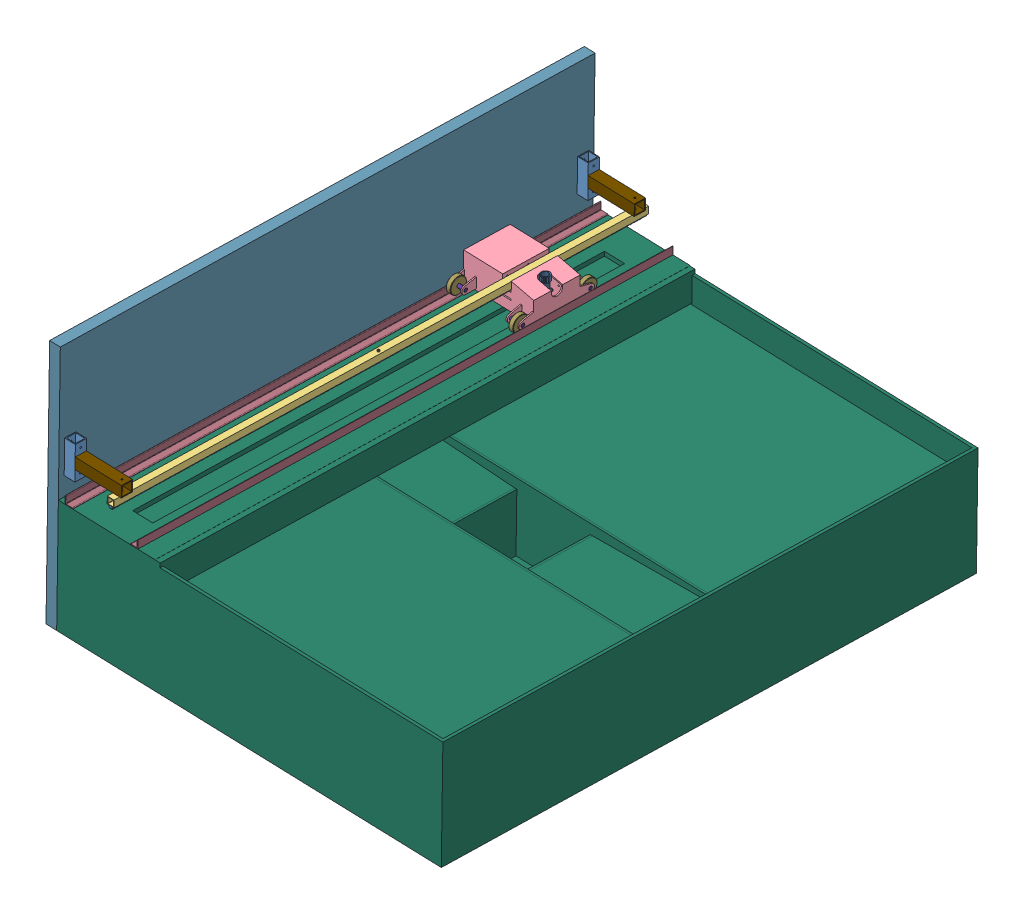
SolidWorks assembly Assembly4, configuration Default. Lengths in mm.
Overall size (969.13 588.82 1240.57).
33 component instances, 21 part files, 57 mates.
Components (placement in the parent):
- 6295K232_MTL GEAR RACK--14-.5 DEG PRESSURE ANGLE-1: 6295K232_MTL GEAR RACK--14-.5 DEG PRESSURE ANGLE [6295K232] at (310.8168 -1313.8551 1072.8368) x (-0.021222 0.003141 0.99977) z (0.999705 -0.011724 0.021258) size (1219.2 6.35 6.35)
- 91251A113_BLACK-OXIDE ALLOY STEEL SOCKET HEAD CAP SCREW-1: 91251A113_BLACK-OXIDE ALLOY STEEL SOCKET HEAD CAP SCREW [91251A113] at (324.3007 -1313.7028 488.7881) x (-0.325939 0.001109 -0.94539) z (-0.011788 -0.999926 0.002892) size (4.65 4.65 22.32)
- RackBacking1-1: RackBacking1 [Default] at (331.9137 -1296.8145 463.4908) x (-0.021222 0.003141 0.99977) z (0.999705 -0.011724 0.021258) size (1219.2 15.88 15.88)
- 91251A113_BLACK-OXIDE ALLOY STEEL SOCKET HEAD CAP SCREW-2: 91251A113_BLACK-OXIDE ALLOY STEEL SOCKET HEAD CAP SCREW [91251A113] at (311.8789 -1313.8675 1072.8599) x (0.97426 -0.010834 0.225168) z (-0.011788 -0.999926 0.002892) size (4.65 4.65 22.32)
- 91251A113_BLACK-OXIDE ALLOY STEEL SOCKET HEAD CAP SCREW-3: 91251A113_BLACK-OXIDE ALLOY STEEL SOCKET HEAD CAP SCREW [91251A113] at (298.4422 -1310.02 1656.8966) x (0.959532 -0.012125 -0.281339) z (-0.011788 -0.999926 0.002892) size (4.65 4.65 22.32)
- Machine Design Assembly 1-2: Machine Design Assembly 1 [Default] at (1783.6413 -1774.7263 1512.3615) x (-0.115648 -0.280931 0.952735) z (-0.993045 0.011368 -0.117189) size (198.29 116.63 182.75)
  - quarterInchCoupler-1: quarterInchCoupler [6412K11] at (-37.8277 473.4587 1102.0251) x (0.998807 -0.00133 -0.04881) z (0.04881 0.054423 0.997324) size (12.7 13.7 19.05) (hidden)
  - Main_Housing-2: Main_Housing [Default] at (-642.996 231.7633 1650.4471) x (0.092068 0.027377 0.995376) z (-0.954087 -0.28371 0.096052) size (167 66 172)
  - Nema23 Stepper Motor-4: Nema23 Stepper Motor [Default] at (-681.5334 251.0803 1647.4525) x (0.954156 0.283479 -0.096052) z (-0.284798 0.958588 -0.000023) size (56.4 82.6 56.4)
  - Stepper Motor Nema 23 Shaft-3: Stepper Motor Nema 23 Shaft [Default] at (-690.7402 248.3426 1547.9149) x (0.995752 -0.001263 -0.092068) z (0.001263 -0.999624 0.027377) size (6.35 100 6.35)
  - Raspberry Pi 3-4: Raspberry Pi 3 [Default] at (-718.0254 233.7658 1618.7368) x (0.092068 0.027377 0.995376) z (-0.954087 -0.28371 0.096052) size (87.38 57.31 18.74)
  - Motor Shield-3: Motor Shield [Default] at (-733.2486 231.7541 1604.1842) x (0.092068 0.027377 0.995376) z (0.285028 -0.958519 0) size (64.5 8 55.5)
  - Stepper Motor Nema 17-3: Stepper Motor Nema 17 [25mm] at (-737.1607 226.7143 1522.6641) x (-0.28371 0.958809 0.013946) z (0.096052 0.013946 0.995279) size (42.3 49 42.3)
  - SolenoidValve-2: SolenoidValve [Default] at (-720.821 271.3165 1521.0428) x (0.954087 0.28371 -0.096052) z (0.103924 -0.012791 0.994503) size (61 71.38 34)
  - 6867K557_MTL GEAR--14-.5 DEG PRESSURE ANGLE-4: 6867K557_MTL GEAR--14-.5 DEG PRESSURE ANGLE [6867K557] at (-690.7402 248.3426 1547.9149) x (-0.995752 0.001263 0.092068) z (-0.092068 -0.027377 -0.995376) size (17.7 17.8 14.31)
  - Main_Housing_Lid_Final-1: Main_Housing_Lid_Final [Default] at (-642.1409 228.8877 1650.4471) x (-0.092068 -0.027377 -0.995376) z (0.285028 -0.958519 0) size (167 106 3) (hidden)
- wheel-2: wheel [Default] at (362.4104 -1345.0753 801.4369) x (-0.000289 -0.881336 -0.472491) z (-0.024275 -0.472345 0.881079) size (37.19 11 37.19)
- wheel-3: wheel [Default] at (213.4543 -1343.3284 798.2695) x (0.018928 -0.171894 -0.984934) z (-0.015201 -0.985046 0.171621) size (37.19 11 37.19)
- wheel-4: wheel [Default] at (366.6783 -1345.5708 647.4936) x (-0.00534 -0.960411 -0.278535) z (-0.023682 -0.27834 0.960191) size (37.19 11 37.19)
- wheel-5: wheel [Default] at (216.7225 -1343.8122 644.3049) x (0.002635 -0.81808 -0.575099) z (-0.024133 -0.574985 0.817808) size (37.19 11 37.19)
- L_Rails-1: L_Rails [Default] at (363.0838 -1344.6368 1683.7834) x (-0.011788 -0.999926 0.002892) z (0.999705 -0.011724 0.021258) size (18.01 1220.02 18.43)
- L_Rails-2: L_Rails [Default] at (216.0262 -1346.441 460.3866) x (-0.011788 -0.999926 0.002892) z (-0.999705 0.011724 -0.021258) size (18.01 1220.02 18.43)
- box-2: box [Default] at (171.2972 -1627.9323 461.1217) x (-0.021222 0.003141 0.99977) z (-0.999705 0.011724 -0.021258) size (1219.2 574 25.4)
- Demo_Enclosure-1: Demo_Enclosure [Default] at (641.1262 -1631.6802 1080.447) x (-0.021222 0.003141 0.99977) z (-0.999705 0.011724 -0.021258) size (1220 264 915)
- 12V DC Water Oil Pump-1: 12V DC Water Oil Pump [Default] at (447.0384 -1543.9402 903.9389) x (0.000017 0.002892 0.999996) z (-0.999931 0.011788 -0.000017) size (45.68 66.45 82.5)
- wheelShaft-6: wheelShaft [Default] at (210.5551 -1343.2944 798.2079) x (-0.009506 -0.994781 -0.101588) z (-0.022338 -0.101356 0.994599) size (8.25 30.9 8.25)
- wheelShaft-7: wheelShaft [Default] at (213.8234 -1343.7782 644.2433) x (-0.009506 -0.994781 -0.101588) z (-0.022338 -0.101356 0.994599) size (8.25 30.9 8.25)
- wheelShaft-8: wheelShaft [Default] at (346.515 -1344.8889 801.0989) x (-0.009506 -0.994781 -0.101588) z (-0.022338 -0.101356 0.994599) size (8.25 30.9 8.25)
- wheelShaft-9: wheelShaft [Default] at (349.7833 -1345.3727 647.1344) x (-0.009506 -0.994781 -0.101588) z (-0.022338 -0.101356 0.994599) size (8.25 30.9 8.25)
- straightBracket-1: straightBracket [Default] at (226.2611 -1295.4652 499.3526) x (0.021222 -0.003141 -0.99977) z (0.999705 -0.011724 0.021258) size (25.4 25.4 110)
- straightBracket2-1: straightBracket2 [Default] at (201.4674 -1244.3712 498.6657) x (0.021222 -0.003141 -0.99977) z (-0.011788 -0.999926 0.002892) size (25.4 25.4 76.2)
- straightBracket-2: straightBracket [Default] at (200.4025 -1291.7824 1667.4611) x (0.021222 -0.003141 -0.99977) z (0.999705 -0.011724 0.021258) size (25.4 25.4 110)
- straightBracket2-2: straightBracket2 [Default] at (201.5404 -1241.066 1641.92) x (-0.021222 0.003141 0.99977) z (-0.011788 -0.999926 0.002892) size (25.4 25.4 76.2)
Mates (geometry in assembly coordinates):
- Parallel1: parallel anti-aligned: cylinder of 6295K232_MTL GEAR RACK--14-.5 DEG PRESSURE ANGLE-1 through (323.2224 -1315.0553 488.7695) axis (0.011788 0.999926 -0.002892) radius 1.9647; cylinder of RackBacking1-1 through (324.5017 -1296.6541 488.7388) axis (-0.011788 -0.999926 0.002892) radius 2
- Coincident2: coincident anti-aligned: plane of 6295K232_MTL GEAR RACK--14-.5 DEG PRESSURE ANGLE-1 through (326.9655 -1312.6325 463.4355) normal (0.011788 0.999926 -0.002892); plane of RackBacking1-1 through (305.8521 -1308.8584 1682.4561) normal (-0.011788 -0.999926 0.002892)
- Concentric4: concentric aligned: cylinder of RackBacking1-1 through (312.1035 -1294.8189 1072.8048) axis (-0.011788 -0.999926 0.002892) radius 2; cylinder of 91251A113_BLACK-OXIDE ALLOY STEEL SOCKET HEAD CAP SCREW-2 through (312.137 -1291.9743 1072.7966) axis (-0.011788 -0.999926 0.002892) radius 2.3241
- Concentric6: concentric aligned: cylinder of 91251A113_BLACK-OXIDE ALLOY STEEL SOCKET HEAD CAP SCREW-1 through (324.5588 -1291.8096 488.7248) axis (-0.011788 -0.999926 0.002892) radius 2.3241; cylinder of RackBacking1-1 through (324.5017 -1296.6541 488.7388) axis (-0.011788 -0.999926 0.002892) radius 2
- Coincident4: coincident anti-aligned: plane of RackBacking1-1 through (306.0393 -1292.9845 1682.4102) normal (0.011788 0.999926 -0.002892); plane of 91251A113_BLACK-OXIDE ALLOY STEEL SOCKET HEAD CAP SCREW-2 through (312.1035 -1294.8189 1072.8048) normal (-0.011788 -0.999926 0.002892)
- Coincident14: coincident aligned: plane of 6295K232_MTL GEAR RACK--14-.5 DEG PRESSURE ANGLE-1 through (301.0162 -1315.1521 1682.3732) normal (0.999705 -0.011724 0.021258); plane of Machine Design Assembly 1-2/6867K557_MTL GEAR--14-.5 DEG PRESSURE ANGLE-4 through (320.8897 -1324.7549 742.4784) normal (0.999705 -0.011724 0.021258)
- Distance1: distance = 13 mm: point of Machine Design Assembly 1-2/6867K557_MTL GEAR--14-.5 DEG PRESSURE ANGLE-4; line of 6295K232_MTL GEAR RACK--14-.5 DEG PRESSURE ANGLE-1 through (326.9655 -1312.6325 463.4355) axis (-0.021222 0.003141 0.99977)
- Parallel6: parallel aligned: plane of RackBacking1-1 through (306.0393 -1292.9845 1682.4102) normal (0.011788 0.999926 -0.002892); plane of Machine Design Assembly 1-2/Main_Housing-2 through (213.7811 -1290.1962 671.0803) normal (0.011788 0.999926 -0.002892)
- Coincident17: coincident aligned: circle of Machine Design Assembly 1-2/Main_Housing-2; cylinder of wheel-2 through (362.4104 -1345.0753 801.4369) axis (0.999705 -0.011724 0.021258) radius 4.125
- Distance2: distance = 24 mm aligned: plane of wheel-2 through (373.4071 -1345.2043 801.6708) normal (0.999705 -0.011724 0.021258); plane of Machine Design Assembly 1-2/Main_Housing-2 through (349.4142 -1344.9229 801.1606) normal (0.999705 -0.011724 0.021258)
- Coincident24: coincident aligned: circle of Machine Design Assembly 1-2/Main_Housing-2; cylinder of wheel-3 through (213.4543 -1343.3284 798.2695) axis (0.999705 -0.011724 0.021258) radius 4.125
- Coincident25: coincident aligned: circle of Machine Design Assembly 1-2/Main_Housing-2; cylinder of wheel-4 through (366.6783 -1345.5708 647.4936) axis (0.999705 -0.011724 0.021258) radius 4.125
- Coincident26: coincident aligned: circle of Machine Design Assembly 1-2/Main_Housing-2; cylinder of wheel-5 through (216.7225 -1343.8122 644.3049) axis (0.999705 -0.011724 0.021258) radius 4.125
- Distance4: distance = 14 mm anti-aligned: plane of wheel-5 through (227.7193 -1343.9412 644.5388) normal (0.999705 -0.011724 0.021258); plane of Machine Design Assembly 1-2/Main_Housing-2 through (241.7152 -1344.1053 644.8364) normal (-0.999705 0.011724 -0.021258)
- Distance5: distance = 14 mm anti-aligned: plane of wheel-4 through (366.6783 -1345.5708 647.4936) normal (-0.999705 0.011724 -0.021258); plane of Machine Design Assembly 1-2/Main_Housing-2 through (352.6825 -1345.4067 647.196) normal (0.999705 -0.011724 0.021258)
- Distance6: distance = 14 mm anti-aligned: plane of wheel-3 through (224.451 -1343.4574 798.5033) normal (0.999705 -0.011724 0.021258); plane of Machine Design Assembly 1-2/Main_Housing-2 through (238.4469 -1343.6215 798.801) normal (-0.999705 0.011724 -0.021258)
- Coincident53: coincident aligned: plane of 6295K232_MTL GEAR RACK--14-.5 DEG PRESSURE ANGLE-1 through (301.091 -1308.8025 1682.3548) normal (-0.021222 0.003141 0.99977); plane of L_Rails-1 through (363.0838 -1344.6368 1683.7834) normal (-0.021222 0.003141 0.99977)
- Coincident54: coincident aligned: plane of 6295K232_MTL GEAR RACK--14-.5 DEG PRESSURE ANGLE-1 through (301.091 -1308.8025 1682.3548) normal (-0.021222 0.003141 0.99977); plane of L_Rails-1 through (363.0838 -1344.6368 1683.7834) normal (-0.021222 0.003141 0.99977)
- Coincident55: coincident aligned: plane of 6295K232_MTL GEAR RACK--14-.5 DEG PRESSURE ANGLE-1 through (301.091 -1308.8025 1682.3548) normal (-0.021222 0.003141 0.99977); plane of L_Rails-2 through (190.1348 -1342.6086 1680.1058) normal (-0.021222 0.003141 0.99977)
- Coincident58: coincident aligned: plane of box-2 through (171.2972 -1627.9323 461.1217) normal (-0.011788 -0.999926 0.002892); plane of Demo_Enclosure-1 through (641.1262 -1631.6802 1080.447) normal (-0.011788 -0.999926 0.002892)
- Distance8: distance = 0.01 mm anti-aligned: cylinder of wheel-4 through (377.6751 -1345.6998 647.7275) axis (-0.999705 0.011724 -0.021258) radius 18.595; plane of L_Rails-1 through (387.2812 -1364.9505 464.08) normal (0.011788 0.999926 -0.002892)
- Parallel27: parallel anti-aligned: plane of RackBacking1-1 through (290.1689 -1292.7984 1682.0727) normal (-0.999705 0.011724 -0.021258); plane of Demo_Enclosure-1 through (206.6988 -1374.3334 460.2762) normal (0.999705 -0.011724 0.021258)
- Parallel32: parallel aligned: plane of Demo_Enclosure-1 through (641.1262 -1631.6802 1080.447) normal (-0.011788 -0.999926 0.002892); plane of 12V DC Water Oil Pump-1 through (458.7842 -1565.5801 904.0013) normal (-0.011788 -0.999926 0.002892)
- Coincident90: coincident anti-aligned: circle of Machine Design Assembly 1-2/Main_Housing-2; cylinder of wheelShaft-9 through (380.6742 -1345.7349 647.7912) axis (-0.999705 0.011724 -0.021258) radius 4.125
- Coincident91: coincident aligned: plane of Machine Design Assembly 1-2/Main_Housing-2 through (379.9538 -1358.1492 674.8212) normal (0.999705 -0.011724 0.021258); plane of wheelShaft-9 through (380.6742 -1345.7349 647.7912) normal (0.999705 -0.011724 0.021258)
- Coincident92: coincident anti-aligned: circle of Machine Design Assembly 1-2/Main_Housing-2; cylinder of wheelShaft-8 through (377.4059 -1345.2512 801.7558) axis (-0.999705 0.011724 -0.021258) radius 4.125
- Coincident93: coincident aligned: plane of Machine Design Assembly 1-2/Main_Housing-2 through (379.9538 -1358.1492 674.8212) normal (0.999705 -0.011724 0.021258); plane of wheelShaft-8 through (377.4059 -1345.2512 801.7558) normal (0.999705 -0.011724 0.021258)
- Coincident94: coincident anti-aligned: circle of wheel-5; cylinder of wheelShaft-7 through (244.7143 -1344.1405 644.9002) axis (-0.999705 0.011724 -0.021258) radius 4.125
- Coincident95: coincident: line of Machine Design Assembly 1-2/Main_Housing-2 through (244.8619 -1335.395 642.7799) axis (-0.017895 0.235862 0.971622); plane of wheelShaft-7 through (244.7143 -1344.1405 644.9002) normal (0.999705 -0.011724 0.021258)
- Concentric19: concentric anti-aligned: cylinder of wheel-3 through (213.4543 -1343.3284 798.2695) axis (0.999705 -0.011724 0.021258) radius 4.125; cylinder of wheelShaft-6 through (241.446 -1343.6567 798.8647) axis (-0.999705 0.011724 -0.021258) radius 4.125
- Coincident96: coincident: line of Machine Design Assembly 1-2/Main_Housing-2 through (242.1322 -1328.7332 774.8269) axis (-0.023384 -0.229752 0.972968); plane of wheelShaft-6 through (241.446 -1343.6567 798.8647) normal (0.999705 -0.011724 0.021258)
- Distance18: distance = 173 mm anti-aligned: plane of L_Rails-1 through (388.9753 -1348.4693 464.0642) normal (0.999705 -0.011724 0.021258); plane of L_Rails-2 through (190.1348 -1342.6086 1680.1058) normal (-0.999705 0.011724 -0.021258)
- Distance19: distance = 16 mm anti-aligned: plane of L_Rails-2 through (190.1348 -1342.6086 1680.1058) normal (-0.999705 0.011724 -0.021258); plane of box-2 through (203.4561 -1054.2724 460.0019) normal (0.999705 -0.011724 0.021258)
- Coincident181: coincident anti-aligned: plane of straightBracket-2 through (200.4025 -1291.7824 1667.4611) normal (-0.999705 0.011724 -0.021258); plane of straightBracket2-2 through (200.6421 -1317.2604 1642.1404) normal (0.999705 -0.011724 0.021258)
- Parallel36: parallel aligned: plane of straightBracket-2 through (310.6695 -1267.6739 1669.726) normal (0.011788 0.999926 -0.002892); plane of straightBracket2-2 through (201.5404 -1241.066 1641.92) normal (0.011788 0.999926 -0.002892)
- Coincident183: coincident: moEndPointRef_w of straightBracket-2; moEndPointRef_w of straightBracket2-2
- Coincident184: coincident anti-aligned: plane of box-2 through (203.4561 -1054.2724 460.0019) normal (0.999705 -0.011724 0.021258); plane of straightBracket2-2 through (175.2496 -1316.9626 1641.6004) normal (-0.999705 0.011724 -0.021258)
- Parallel38: parallel aligned: plane of box-2 through (178.0636 -1053.9746 459.4619) normal (0.011788 0.999926 -0.002892); plane of straightBracket-2 through (310.6695 -1267.6739 1669.726) normal (0.011788 0.999926 -0.002892)
- Coincident187: coincident anti-aligned: plane of RackBacking1-1 through (306.0393 -1292.9845 1682.4102) normal (0.011788 0.999926 -0.002892); plane of straightBracket-2 through (310.3701 -1293.0721 1669.7995) normal (-0.011788 -0.999926 0.002892)
- Concentric20: concentric aligned: circle of RackBacking1-1; cylinder of 91251A113_BLACK-OXIDE ALLOY STEEL SOCKET HEAD CAP SCREW-3 through (298.7003 -1288.1268 1656.8333) axis (-0.011788 -0.999926 0.002892) radius 2.3241
- Concentric22: concentric anti-aligned: cylinder of 6295K232_MTL GEAR RACK--14-.5 DEG PRESSURE ANGLE-1 through (298.4261 -1311.3849 1656.9005) axis (0.011788 0.999926 -0.002892) radius 1.9647; cylinder of 91251A113_BLACK-OXIDE ALLOY STEEL SOCKET HEAD CAP SCREW-3 through (298.7003 -1288.1268 1656.8333) axis (-0.011788 -0.999926 0.002892) radius 2.3241
- Coincident189: coincident anti-aligned: plane of RackBacking1-1 through (306.0393 -1292.9845 1682.4102) normal (0.011788 0.999926 -0.002892); plane of straightBracket-2 through (310.3701 -1293.0721 1669.7995) normal (-0.011788 -0.999926 0.002892)
- Concentric23: concentric aligned: cylinder of 91251A113_BLACK-OXIDE ALLOY STEEL SOCKET HEAD CAP SCREW-3 through (298.7003 -1288.1268 1656.8333) axis (-0.011788 -0.999926 0.002892) radius 2.3241; circle of straightBracket-2
- Coincident194: coincident anti-aligned: plane of straightBracket-1 through (226.2611 -1295.4652 499.3526) normal (-0.999705 0.011724 -0.021258); plane of straightBracket2-1 through (225.9616 -1320.8634 499.426) normal (0.999705 -0.011724 0.021258)
- Parallel39: parallel aligned: plane of straightBracket-1 through (336.5281 -1271.3568 501.6175) normal (0.011788 0.999926 -0.002892); plane of straightBracket2-1 through (201.4674 -1244.3712 498.6657) normal (0.011788 0.999926 -0.002892)
- Coincident196: coincident: moEndPointRef_w of straightBracket-1; moEndPointRef_w of straightBracket2-1
- Parallel40: parallel aligned: plane of box-2 through (178.0636 -1053.9746 459.4619) normal (0.011788 0.999926 -0.002892); plane of straightBracket2-1 through (201.4674 -1244.3712 498.6657) normal (0.011788 0.999926 -0.002892)
- Concentric24: concentric aligned: cylinder of RackBacking1-1 through (324.5017 -1296.6541 488.7388) axis (-0.011788 -0.999926 0.002892) radius 2; cylinder of straightBracket-1 through (324.8011 -1271.256 488.6654) axis (-0.011788 -0.999926 0.002892) radius 2
- Coincident203: coincident anti-aligned: plane of RackBacking1-1 through (306.0393 -1292.9845 1682.4102) normal (0.011788 0.999926 -0.002892); plane of straightBracket-1 through (336.2286 -1296.7549 501.691) normal (-0.011788 -0.999926 0.002892)
- Coincident204: coincident anti-aligned: plane of L_Rails-1 through (388.7631 -1366.4679 464.1162) normal (-0.011788 -0.999926 0.002892); plane of Demo_Enclosure-1 through (644.2382 -1367.6996 1079.6836) normal (0.011788 0.999926 -0.002892)
- Coincident207: coincident anti-aligned: plane of L_Rails-2 through (189.9226 -1360.6072 1680.1578) normal (-0.011788 -0.999926 0.002892); plane of Demo_Enclosure-1 through (644.2382 -1367.6996 1079.6836) normal (0.011788 0.999926 -0.002892)
- Coincident210: coincident anti-aligned: plane of box-2 through (203.4561 -1054.2724 460.0019) normal (0.999705 -0.011724 0.021258); plane of Demo_Enclosure-1 through (199.7009 -1374.2514 460.1274) normal (-0.999705 0.011724 -0.021258)
- Coincident212: coincident aligned: plane of RackBacking1-1 through (306.0393 -1292.9845 1682.4102) normal (-0.021222 0.003141 0.99977); plane of Demo_Enclosure-1 through (173.8094 -1370.4189 1679.8466) normal (-0.021222 0.003141 0.99977)
- Coincident213: coincident anti-aligned: plane of 91251A113_BLACK-OXIDE ALLOY STEEL SOCKET HEAD CAP SCREW-1 through (324.5253 -1294.6542 488.733) normal (-0.011788 -0.999926 0.002892); plane of straightBracket-1 through (336.2947 -1294.7613 499.6856) normal (0.011788 0.999926 -0.002892)
- Coincident214: coincident anti-aligned: plane of 91251A113_BLACK-OXIDE ALLOY STEEL SOCKET HEAD CAP SCREW-3 through (298.6667 -1290.9714 1656.8415) normal (-0.011788 -0.999926 0.002892); plane of straightBracket-2 through (310.4361 -1291.0785 1667.7941) normal (0.011788 0.999926 -0.002892)
- Coincident215: coincident aligned: plane of box-2 through (152.1891 -1050.1447 1678.3813) normal (-0.021222 0.003141 0.99977); plane of Demo_Enclosure-1 through (173.8094 -1370.4189 1679.8466) normal (-0.021222 0.003141 0.99977)
- Parallel41: parallel anti-aligned: plane of box-2 through (203.4561 -1054.2724 460.0019) normal (0.999705 -0.011724 0.021258); plane of straightBracket2-1 through (200.5691 -1320.5656 498.8861) normal (-0.999705 0.011724 -0.021258)
